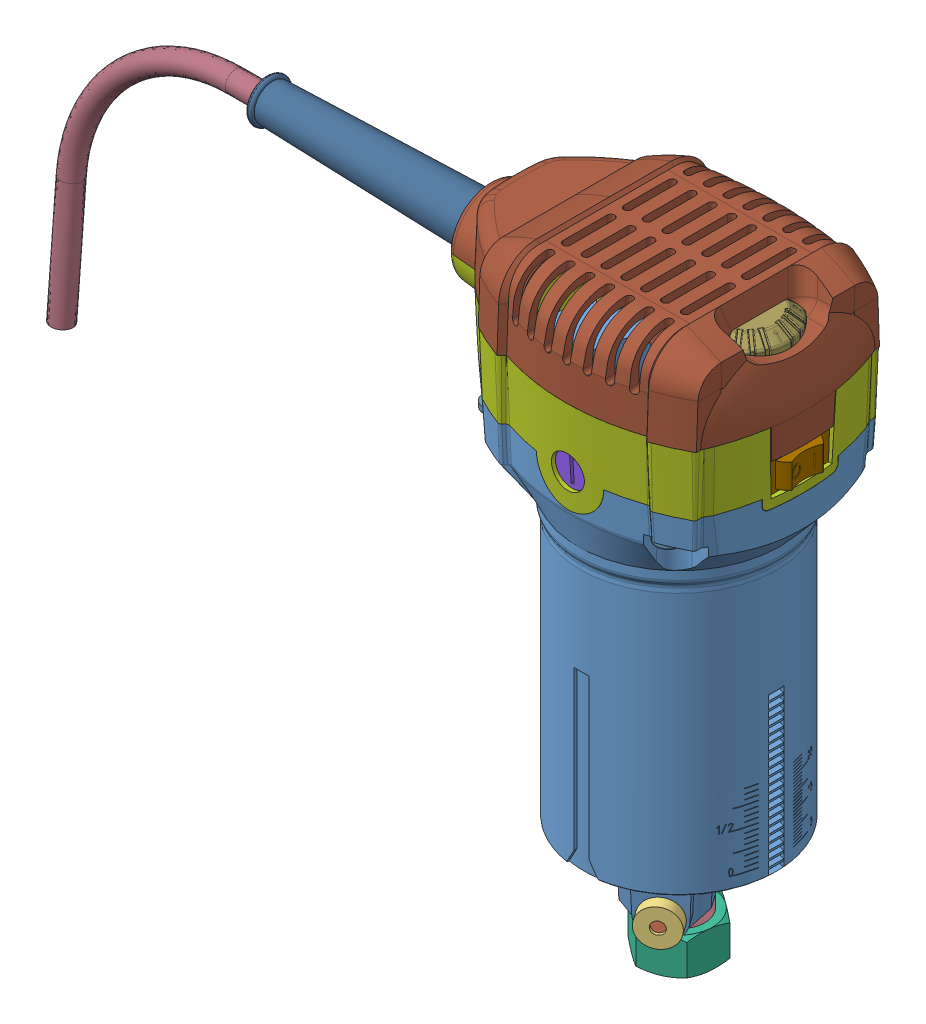
SolidWorks assembly Router, configuration Standard. Lengths in mm.
Overall size (242.76 200.91 76.57).
18 component instances, 14 part files, 40 mates.
Components (placement in the parent):
- OuterHousing-1: OuterHousing [Standard] x (-1 0 0) z (0 0 1) size (94.56 135.68 76.01)
- Pin4-1: Pin4 [Standard] at (15.4866 -128.1491 22.1171) x (-0.573576 0 -0.819152) z (-0.801509 0.206427 0.561223) size (18 7 7)
- PushButtom-1: PushButtom [Standard] at (16.0601 -128.1491 22.9363) x (-0.573576 0 -0.819152) z (0.809245 -0.155055 -0.566639) size (4 12 12)
- Spindle-1: Spindle [Standard] at (0 -109 0) x (0 -1 0) z (-0.067231 0 -0.997737) size (39 22 22)
- ColletChuck8mm-1: ColletChuck8mm [Standard] at (0 -150.866 0) x (0 1 0) z (0.772797 0 -0.634654) size (9 14 13.99)
- ColletNut-1: ColletNut [Standard] at (0 -153.866 0) x (-0.91755 0 0.39762) z (-0.39762 0 -0.91755) size (25.4 12 22)
- InnerHousing-1: InnerHousing [Standard] x (-1 0 0) z (0 0 -1) size (102.82 31.15 74.41)
- BrushHolderCap-1: BrushHolderCap [Standard] at (0 0 35) x (0.997931 0.064293 0) z (-0.064293 0.997931 0) size (12 6 12)
- BrushHolderCap-2: BrushHolderCap [Standard] at (0 0 -29) x (0.997931 0.064293 0) z (-0.064293 0.997931 0) size (12 6 12)
- Switch-1: Switch [Standard] at (36 4.1 0) x (0 0 -1) z (0 -1 0) size (30 5.15 12)
- CordGuard-1: CordGuard [Standard] at (-55 20 0) x (-1 0 0) z (0 0.924225 0.381849) size (80 20 20)
- TopCover-1: TopCover [Standard] at (0 20 0) x (-1 0 0) z (0 0 -1) size (103.57 37.04 76.02)
- SpeedController-1: SpeedController [Standard] at (22 31.536 0) x (0.624108 0 -0.781338) z (0.781338 0 0.624108) size (28 8.06 28.07)
- Cord-1: Cord [Standard] at (-125 20 0) x (-1 0 0) z (0 -0.078529 -0.996912) size (73.5 93.5 7)
- pan head cross recess screw_iso-1: pan head cross recess screw_iso [ISO 7045 - M4 x 40 - Z - 40N] at (-41 -12.1 19) x (0 1 0) z (0 0 1) size (43.02 8 8)
- pan head cross recess screw_iso-2: pan head cross recess screw_iso [ISO 7045 - M4 x 40 - Z - 40N] at (25 -12.1 28.5) x (0 1 0) z (0 0 1) size (43.02 8 8)
- pan head cross recess screw_iso-3: pan head cross recess screw_iso [ISO 7045 - M4 x 40 - Z - 40N] at (25 -12.1 -28.5) x (0 1 0) z (0 0 1) size (43.02 8 8)
- pan head cross recess screw_iso-4: pan head cross recess screw_iso [ISO 7045 - M4 x 40 - Z - 40N] at (-41 -12.1 -19) x (0 1 0) z (0 0 1) size (43.02 8 8)
Mates (geometry in assembly coordinates):
- Deckungsgleich1: coincident anti-aligned: plane of OuterHousing-1 through (0 0 0) normal (0 -1 0)
- Deckungsgleich2: coincident aligned: plane of OuterHousing-1 through (0 0 0) normal (0 0 1)
- Deckungsgleich3: coincident anti-aligned: plane of OuterHousing-1 through (0 0 0) normal (-1 0 0)
- Konzentrisch1: concentric aligned: cylinder of OuterHousing-1 through (-34.6676 -128.1491 -49.5104) axis (0.573576 0 0.819152) radius 2.5; cylinder of Pin4-1 through (15.4866 -128.1491 22.1171) axis (0.573576 0 0.819152) radius 2.5
- Konzentrisch2: concentric aligned: cylinder of Pin4-1 through (15.4866 -128.1491 22.1171) axis (0.573576 0 0.819152) radius 2; cylinder of PushButtom-1 through (16.0601 -128.1491 22.9363) axis (0.573576 0 0.819152) radius 2
- Deckungsgleich5: coincident anti-aligned: plane of Pin4-1 through (13.4276 -130.106 19.8965) normal (0.573576 0 0.819152); plane of PushButtom-1 through (14.5279 -122.2216 19.126) normal (-0.573576 0 -0.819152)
- Abstand2: distance = 9 mm: plane of Pin4-1 through (4.7395 -130.5952 7.6684) normal (-0.573576 0 -0.819152); line of OuterHousing-1 through (0 0 0) axis (0 -1 0)
- Konzentrisch3: concentric anti-aligned: cylinder of OuterHousing-1 through (0 -82.5442 0) axis (0 -1 0) radius 9; cylinder of Spindle-1 through (0 -109 0) axis (0 1 0) radius 8.5
- Abstand3: distance = 10 mm anti-aligned: plane of Spindle-1 through (-10.9751 -111 0.7395) normal (0 -1 0); plane of OuterHousing-1 through (0 -121 0) normal (0 1 0)
- Konzentrisch4: concentric anti-aligned: cylinder of Spindle-1 through (0 -109 0) axis (0 1 0) radius 4.5; cylinder of ColletCone8mm-1 through (0 -150.866 0) axis (0 -1 0) radius 4
- Deckungsgleich6: coincident aligned: cone of Spindle-1 through (0 -148 0) axis (0 1 0); cylinder of ColletCone8mm-1 through (0 -141.866 0) axis (0 1 0) radius 261.7994
- Konzentrisch5: concentric anti-aligned: cylinder of Spindle-1 through (0 -109 0) axis (0 1 0) radius 8.5; cylinder of ColletNut-1 through (0 -150.866 0) axis (0 -1 0) radius 5
- Deckungsgleich7: coincident anti-aligned: plane of ColletCone8mm-1 through (4.4426 -150.866 5.4096) normal (0 -1 0); plane of ColletNut-1 through (0 -150.866 0) normal (0 1 0)
- Deckungsgleich8: coincident anti-aligned: plane of OuterHousing-1 through (0 0 0) normal (0 1 0); plane of InnerHousing-1 through (-11 0 37.2055) normal (0 -1 0)
- Deckungsgleich9: coincident anti-aligned: plane of InnerHousing-1 through (0 0 0) normal (0 0 -1)
- Deckungsgleich12: coincident anti-aligned: plane of InnerHousing-1 through (0 0 0) normal (-1 0 0)
- Konzentrisch6: concentric anti-aligned: cylinder of InnerHousing-1 through (0 0 0) axis (0 0 -1) radius 5.4; cylinder of BrushHolderCap-1 through (0 0 29) axis (0 0 1) radius 6
- Abstand4: distance = 35 mm anti-aligned: plane of BrushHolderCap-1 through (0 0 35) normal (0 0 1); plane of InnerHousing-1 through (0 0 0) normal (0 0 -1)
- Konzentrisch7: concentric aligned: cylinder of InnerHousing-1 through (0 0 0) axis (0 0 1) radius 5.4; cylinder of BrushHolderCap-2 through (0 0 -35) axis (0 0 1) radius 6
- Abstand5: distance = 35 mm aligned: plane of BrushHolderCap-2 through (0 0 -35) normal (0 0 -1); plane of InnerHousing-1 through (0 0 0) normal (0 0 -1)
- Abstand6: distance = 1 mm anti-aligned: plane of Switch-1 through (36 0.1 0) normal (0 -1 0); plane of InnerHousing-1 through (41.5539 -0.9 -10) normal (0 1 0)
- Abstand7: distance = 37 mm anti-aligned: plane of Switch-1 through (37 4.1 0) normal (-1 0 0)
- Deckungsgleich17: coincident anti-aligned: plane of Switch-1 through (36 4.1 0) normal (0 0 -1)
- Konzentrisch8: concentric aligned: cylinder of InnerHousing-1 through (0 20 0) axis (1 0 0) radius 10; cylinder of CordGuard-1 through (-55 20 0) axis (1 0 0) radius 10
- Deckungsgleich18: coincident anti-aligned: plane of InnerHousing-1 through (-59 20 8) normal (1 0 0); plane of CordGuard-1 through (-59 16.1815 9.2422) normal (-1 0 0)
- Konzentrisch9: concentric anti-aligned: cylinder of OuterHousing-1 through (-41 -135.001 19) axis (0 1 0) radius 2.25; cylinder of pan head cross recess screw_iso-1 through (-41 -37.5 19) axis (0 -1 0) radius 4
- Deckungsgleich19: coincident anti-aligned: plane of OuterHousing-1 through (-40.691 -9 18.5) normal (0 -1 0); plane of pan head cross recess screw_iso-1 through (-43 -9 19) normal (0 1 0)
- Konzentrisch10: concentric anti-aligned: cylinder of OuterHousing-1 through (25 -135.001 28.5) axis (0 1 0) radius 2.25; cylinder of pan head cross recess screw_iso-2 through (25 -37.5 28.5) axis (0 -1 0) radius 4
- Deckungsgleich20: coincident anti-aligned: plane of OuterHousing-1 through (26.309 -9 28.5) normal (0 -1 0); plane of pan head cross recess screw_iso-2 through (23 -9 28.5) normal (0 1 0)
- Konzentrisch11: concentric anti-aligned: cylinder of OuterHousing-1 through (25 -135.001 -28.5) axis (0 1 0) radius 2.25; cylinder of pan head cross recess screw_iso-3 through (25 -37.5 -28.5) axis (0 -1 0) radius 4
- Deckungsgleich21: coincident anti-aligned: plane of OuterHousing-1 through (26.309 -9 -28.5) normal (0 -1 0); plane of pan head cross recess screw_iso-3 through (23 -9 -28.5) normal (0 1 0)
- Konzentrisch12: concentric anti-aligned: cylinder of OuterHousing-1 through (-41 -135.001 -19) axis (0 1 0) radius 2.25; cylinder of pan head cross recess screw_iso-4 through (-41 -37.5 -19) axis (0 -1 0) radius 4
- Deckungsgleich22: coincident anti-aligned: plane of OuterHousing-1 through (-40.691 -9 -18.5) normal (0 -1 0); plane of pan head cross recess screw_iso-4 through (-43 -9 -19) normal (0 1 0)
- Deckungsgleich24: coincident anti-aligned: plane of TopCover-1 through (0 20 0) normal (0 0 -1)
- Deckungsgleich25: coincident anti-aligned: plane of TopCover-1 through (0 20 0) normal (-1 0 0)
- Deckungsgleich26: coincident aligned: plane of InnerHousing-1 through (0 20 0) normal (0 1 0); plane of TopCover-1 through (0 20 0) normal (0 1 0)
- Deckungsgleich27: coincident anti-aligned: plane of TopCover-1 through (8 31.536 0) normal (0 1 0); plane of Controller-1 through (22 31.536 0) normal (0 -1 0)
- Konzentrisch13: concentric aligned: cylinder of TopCover-1 through (22 16.3555 0) axis (0 -1 0) radius 14; cylinder of Controller-1 through (22 39.536 0) axis (0 -1 0) radius 14
- Konzentrisch14: concentric anti-aligned: circle of CordGuard-1; circle of Cord-1
- Abstand8: distance = 10 mm anti-aligned: plane of CordGuard-1 through (-135 17.3271 6.4696) normal (-1 0 0); plane of Cord-1 through (-125 20 0) normal (1 0 0)
